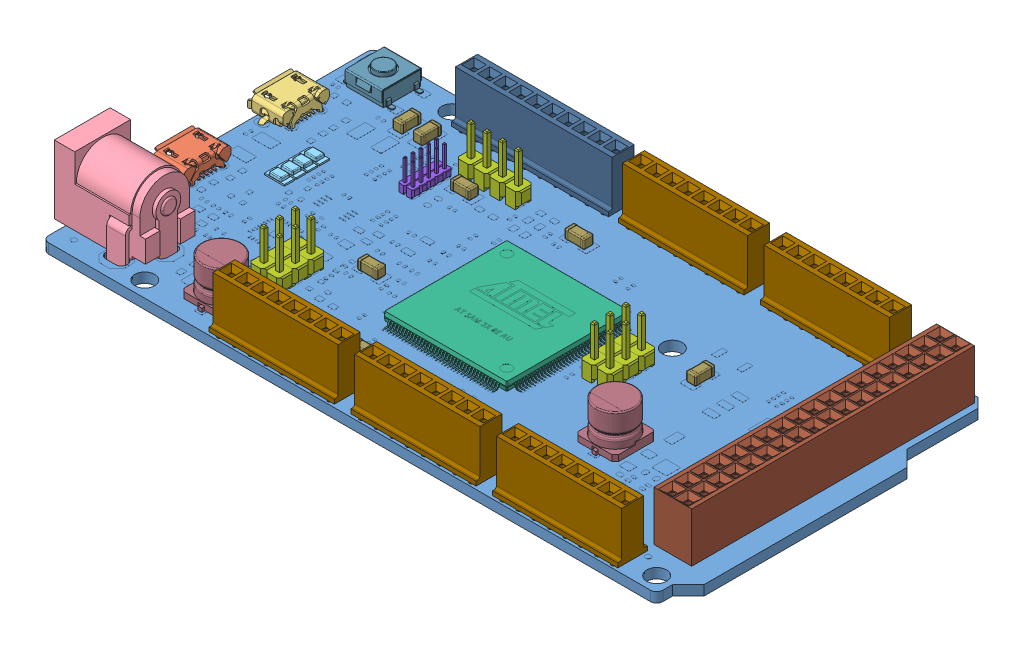
SolidWorks assembly ARDUINO DUE2, configuration Default. Lengths in mm.
Overall size (103.48 14.6 53.34).
37 component instances, 14 part files, 0 mates.
Components (placement in the parent):
- PCB - Arduino-1: PCB - Arduino [Default] at origin size (101.6 1.62 53.34)
- MicroUSB B - Hirose - ZX62D-B-5P8-1: MicroUSB B - Hirose - ZX62D-B-5P8 [Default] at (4.425 1.1 -18.8) x (-1 0 0) z (0 0 -1) size (5.8 3.51 8.09)
- MicroUSB AB - Hirose - ZX62D-AB-5P8-1: MicroUSB AB - Hirose - ZX62D-AB-5P8 [Default] at (0.225 2.74 -38.1) size (5.9 3.4 8.66)
- Power Jack - Kycon - KLDHCX-0202-A-1: Power Jack - Kycon - KLDHCX-0202-A [Default] at (-1.88 6.3 -8.302) x (0 0 1) z (-1 0 0) size (9.6 14.6 14.2)
- LED - Kingbright - KPT-3216EC-1: LED - Kingbright - KPT-3216EC [Default] at (10.541 0.8 -31.4452) size (3.2 0.75 1.6)
- LED - Kingbright - KPT-3216EC-2: LED - Kingbright - KPT-3216EC [Default] at (10.541 0.8 -33.3248) size (3.2 0.75 1.6)
- LED - Kingbright - KPT-3216EC-3: LED - Kingbright - KPT-3216EC [Default] at (10.541 0.8 -27.686) size (3.2 0.75 1.6)
- LED - Kingbright - KPT-3216EC-4: LED - Kingbright - KPT-3216EC [Default] at (10.541 0.8 -29.5656) size (3.2 0.75 1.6)
- Microchip - Atmel - SAM3X8EAU-1: Microchip - Atmel - SAM3X8EAU [Default] at (48.895 1.5 -26.015) size (22 1.5 22)
- Berg Header - 2.54 x 2-1: Berg Header - 2.54 x 2 [Default] at (32.004 3.35 -43.4848) size (5.08 10.05 2.54)
- Berg Header - 2.54 x 2-2: Berg Header - 2.54 x 2 [Default] at (26.924 3.35 -43.4848) size (5.08 10.05 2.54)
- Berg Header - 2.54 x 2-3: Berg Header - 2.54 x 2 [Default] at (24.7888 3.35 -17.272) size (5.08 10.05 2.54)
- Berg Header - 2.54 x 2-4: Berg Header - 2.54 x 2 [Default] at (24.7888 3.35 -14.732) size (5.08 10.05 2.54)
- Berg Header - 2.54 x 2-5: Berg Header - 2.54 x 2 [Default] at (24.7888 3.35 -12.192) size (5.08 10.05 2.54)
- Berg Header - 2.54 x 2-6: Berg Header - 2.54 x 2 [Default] at (64.897 3.35 -30.48) size (5.08 10.05 2.54)
- Berg Header - 2.54 x 2-7: Berg Header - 2.54 x 2 [Default] at (64.897 3.35 -27.94) size (5.08 10.05 2.54)
- Berg Header - 2.54 x 2-8: Berg Header - 2.54 x 2 [Default] at (64.897 3.35 -25.4) size (5.08 10.05 2.54)
- Berg Header - 1.27 x 10-1: Berg Header - 1.27 x 10 [Default] at (23.1644 2.4313 -38.5064) size (2.54 6.87 6.35)
- Berg Header Receptacle 2.54 x 8 - FCI - 66951-008LF-1: Berg Header Receptacle 2.54 x 8 - FCI - 66951-008LF [Default] at (54.61 1.1302 -50.8) size (20.19 11.89 4.78)
- Berg Header Receptacle 2.54 x 8 - FCI - 66951-008LF-2: Berg Header Receptacle 2.54 x 8 - FCI - 66951-008LF [Default] at (77.47 1.1302 -50.8) size (20.19 11.89 4.78)
- Berg Header Receptacle 2.54 x 8 - FCI - 66951-008LF-3: Berg Header Receptacle 2.54 x 8 - FCI - 66951-008LF [Default] at (36.83 1.1302 -2.54) size (20.19 11.89 4.78)
- Berg Header Receptacle 2.54 x 8 - FCI - 66951-008LF-4: Berg Header Receptacle 2.54 x 8 - FCI - 66951-008LF [Default] at (59.69 1.1302 -2.54) size (20.19 11.89 4.78)
- Berg Header Receptacle 2.54 x 8 - FCI - 66951-008LF-5: Berg Header Receptacle 2.54 x 8 - FCI - 66951-008LF [Default] at (82.55 1.1302 -2.54) size (20.19 11.89 4.78)
- Berg Header Receptacle 2.54 x 10 - FCI - 66951-010LF-1: Berg Header Receptacle 2.54 x 10 - FCI - 66951-010LF [Default] at (30.226 1.1302 -50.8) size (25.27 11.89 4.78)
- Berg Header Receptacle 2.54 x 36 - FCI - 66953-018LF-1: Berg Header Receptacle 2.54 x 36 - FCI - 66953-018LF [Default] at (95.25 1.054 -29.21) x (0 0 1) z (-1 0 0) size (45.59 11.81 6.1)
- Capacitor-1: Capacitor [Default] at (13.73 1.6 -45.09) x (0 0 1) z (-1 0 0) size (3.2 1.6 1.6)
- Capacitor-2: Capacitor [Default] at (16.98 1.6 -45.09) x (0 0 1) z (-1 0 0) size (3.2 1.6 1.6)
- Capacitor-3: Capacitor [Default] at (31.25 1.6 -21.86) size (3.2 1.6 1.6)
- Capacitor-4: Capacitor [Default] at (43.7 1.6 -42.84) size (3.2 1.6 1.6)
- Capacitor-5: Capacitor [Default] at (72.62 1.6 -33.54) x (0 0 1) z (-1 0 0) size (3.2 1.6 1.6)
- Capacitor-6: Capacitor [Default] at (42.5 1.6 -9.55) size (3.2 1.6 1.6)
- Capacitor-7: Capacitor [Default] at (36.4 1.6 -9.55) size (3.2 1.6 1.6)
- Capacitor-8: Capacitor [Default] at (86.68 1.6 -17.04) x (0 0 1) z (-1 0 0) size (3.2 1.6 1.6)
- Capacitor-9: Capacitor [Default] at (27.6 1.6 -40.44) size (3.2 1.6 1.6)
- Capacitor - Nichicon - UUR1C101MCL1GS-1: Capacitor - Nichicon - UUR1C101MCL1GS [Default] at (22.83 -0.584 -6) size (6.5 6.43 6.85)
- Capacitor - Nichicon - UUR1C101MCL1GS-2: Capacitor - Nichicon - UUR1C101MCL1GS [Default] at (74.6 -0.584 -17.75) size (6.5 6.43 6.85)
- Switch - ESwitch - TLE3303-1: Switch - ESwitch - TLE3303 [Default] at (6.25 0.85 -48.74) size (8 3.15 6.71)
